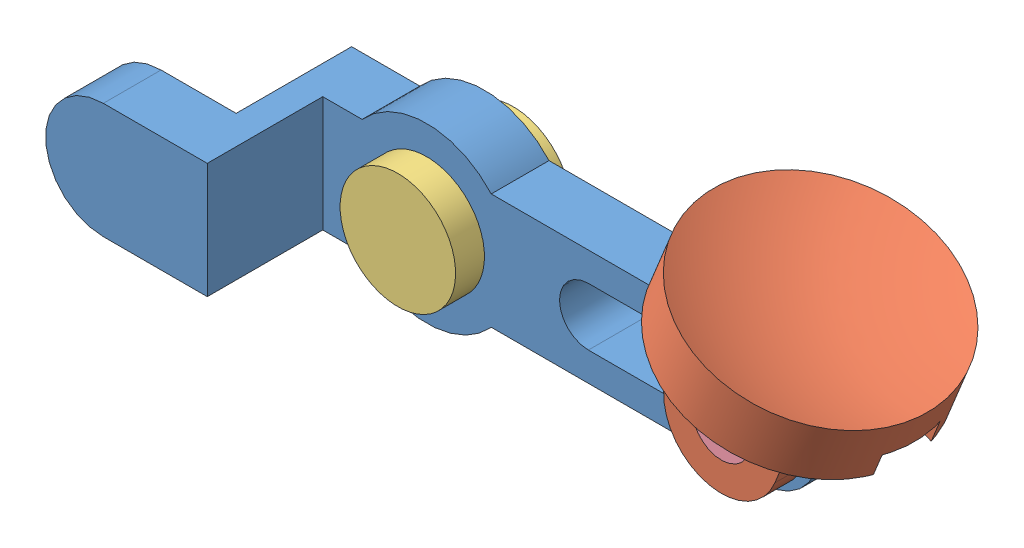
SolidWorks assembly Marble Reloading System, configuration Default. Lengths in mm.
Overall size (81.11 26.66 28.57).
4 component instances, 4 part files, 6 mates.
Components (placement in the parent):
- Stepper Arm-1: Stepper Arm [Default] at origin size (72.39 19.05 19.05)
- Basket Receiver for Stepper-1: Basket Receiver for Stepper [Default] at (37.7424 5.2901 0) x (0.925655 -0.378369 0) z (0 0 1) size (25.4 18.41 25.4)
- Big Pin for Marble Recapture-1: Big Pin for Marble Recapture [Default] at (0 0 -6.35) x (0.996964 0.077862 0) z (0 0 1) size (15.88 15.88 15.88)
- Small Pin for Marble Recapture-1: Small Pin for Marble Recapture [Default] at (35.58 0 -6.35) size (10.16 10.16 15.88)
Mates (geometry in assembly coordinates):
- Symmetric2: symmetric aligned: plane of Stepper Arm-1 through (0 0 0) normal (0 0 1); plane of Basket Receiver for Stepper-1 through (35.58 0 -3.175) normal (0 0 1); plane of Basket Receiver for Stepper-1 through (35.58 0 3.175) normal (0 0 -1)
- Slot1: slot anti-aligned: cylinder of Basket Receiver for Stepper-1 through (35.58 0 -6.35) axis (0 0 1) radius 3.175; cylinder of Stepper Arm-1 through (36.83 0 21.1355) axis (0 0 -1) radius 3.175; cylinder of Stepper Arm-1 through (17.78 0 -29.3567) axis (0 0 1) radius 3.175
- Concentric1: concentric aligned: cylinder of Stepper Arm-1 through (0 0 3.175) axis (0 0 -1) radius 6.35; cylinder of Big Pin for Marble Recapture-1 through (0 0 6.35) axis (0 0 -1) radius 5.85
- Concentric2: concentric anti-aligned: cylinder of Basket Receiver for Stepper-1 through (35.58 0 -6.35) axis (0 0 1) radius 3.175; cylinder of Small Pin for Marble Recapture-1 through (35.58 0 6.35) axis (0 0 -1) radius 2.675
- Coincident1: coincident aligned: plane of Basket Receiver for Stepper-1 through (35.58 0 -6.35) normal (0 0 -1); plane of Small Pin for Marble Recapture-1 through (35.58 0 -6.35) normal (0 0 -1)
- Symmetric3: symmetric aligned: plane of Stepper Arm-1 through (0 0 0) normal (0 0 1); plane of Big Pin for Marble Recapture-1 through (0 0 -6.35) normal (0 0 -1); plane of Big Pin for Marble Recapture-1 through (0 0 6.35) normal (0 0 1)
